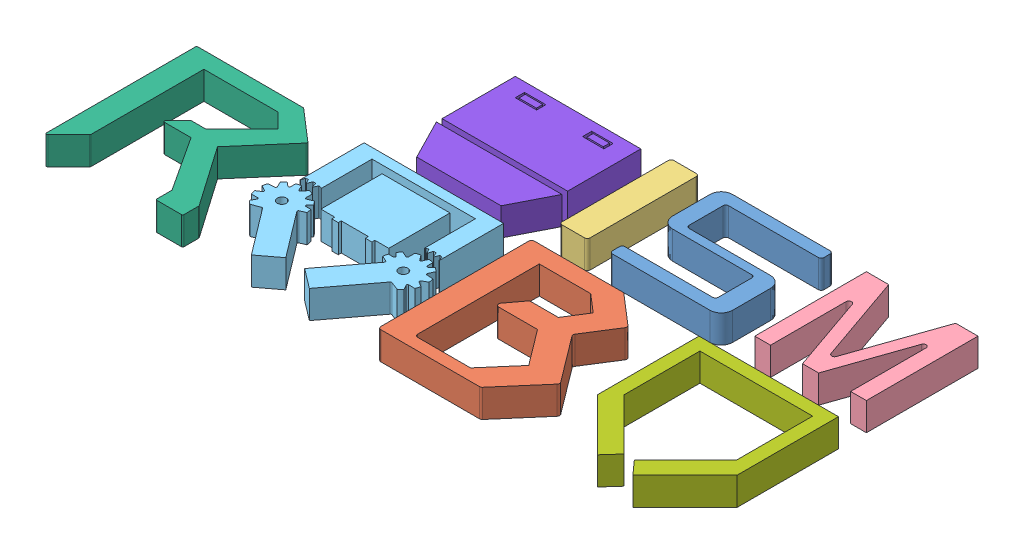
SolidWorks assembly Assem1, configuration Default. Lengths in mm.
Overall size (230 10 105).
8 component instances, 8 part files, 21 mates.
Components (placement in the parent):
- LETTER S-1: LETTER S [Default] at (-18.8633 11.7373 60.793) size (40 10 40)
- letterB-1: letterB [Default] at (-36.8633 11.7373 125.793) size (49.72 10 55)
- letterI-1: letterI [Default] at (-36.8633 11.7373 60.793) size (10 10 40)
- LetterM-1: LetterM [Default] at (33.1367 11.7373 60.793) size (40 10 40)
- letterO-1: letterO [Default] at (-96.8633 11.7373 125.793) size (59.86 10 55)
- letterR-1: letterR [Default] at (-156.8633 11.7373 125.793) size (50 10 55)
- Part5-1: Part5 [Default] at (23.1367 11.7373 125.793) size (50 10 55)
- symbol-1: symbol [Default] at (-90.391 11.7373 63.0891) size (45 10 42.7)
Mates (geometry in assembly coordinates):
- Coincident15: coincident: plane of letterO-1 through (-96.8633 21.7373 125.793) normal (0 1 0); plane of letterR-1 through (-156.8633 21.7373 135.3346) normal (0 1 0)
- Distance4: distance = 10 mm anti-aligned: plane of letterO-1 through (-46.8633 21.7373 125.793) normal (1 0 0); plane of letterB-1 through (-36.8633 21.7373 125.793) normal (-1 0 0)
- Coincident17: coincident aligned: plane of letterB-1 through (-48.8633 21.7373 125.793) normal (0 1 0); plane of letterO-1 through (-108.8633 21.7373 125.793) normal (0 1 0)
- Distance6: distance = 60 mm aligned: plane of letterB-1 through (-36.8633 21.7373 125.793) normal (-1 0 0); plane of Part5-1 through (23.1367 21.7373 107.117) normal (-1 0 0)
- Coincident21: coincident aligned: plane of letterB-1 through (-48.8633 21.7373 125.793) normal (0 1 0); plane of Part5-1 through (11.1367 21.7373 125.793) normal (0 1 0)
- Coincident22: coincident aligned: plane of letterB-1 through (-48.8633 21.7373 70.793) normal (0 0 -1); plane of Part5-1 through (11.1367 21.7373 70.793) normal (0 0 -1)
- Distance7: distance = 60 mm: plane of letterR-1 through (-156.8633 21.7373 125.793) normal (-1 0 0); plane of letterO-1 through (-96.8633 21.7373 125.793) normal (-1 0 0)
- Coincident28: coincident aligned: plane of letterO-1 through (-108.8633 21.7373 125.793) normal (0 1 0); plane of symbol-1 through (-102.391 21.7373 63.0891) normal (0 1 0)
- Distance9: distance = 5 mm anti-aligned: plane of symbol-1 through (-90.391 21.7373 65.793) normal (0 0 1); plane of letterO-1 through (-96.8633 21.7373 70.793) normal (0 0 -1)
- Coincident31: coincident anti-aligned: plane of letterO-1 through (-102.391 21.7373 125.793) normal (1 0 0); plane of symbol-1 through (-102.391 21.7373 63.0891) normal (-1 0 0)
- Coincident33: coincident aligned: plane of letterB-1 through (-48.8633 21.7373 125.793) normal (0 1 0); plane of letterI-1 through (-48.8633 21.7373 60.793) normal (0 1 0)
- Coincident37: coincident aligned: plane of letterB-1 through (-48.8633 21.7373 125.793) normal (-1 0 0); plane of letterI-1 through (-48.8633 21.7373 60.793) normal (-1 0 0)
- Coincident38: coincident aligned: plane of letterB-1 through (-48.8633 21.7373 70.793) normal (0 0 -1); plane of letterO-1 through (-108.8633 21.7373 70.793) normal (0 0 -1)
- Distance11: distance = 10 mm anti-aligned: plane of letterB-1 through (-36.8633 21.7373 70.793) normal (0 0 -1); plane of letterI-1 through (-36.8633 21.7373 60.793) normal (0 0 1)
- Coincident40: coincident aligned: plane of LETTER S-1 through (-18.8633 21.7373 60.793) normal (0 1 0); plane of letterI-1 through (-48.8633 21.7373 60.793) normal (0 1 0)
- Coincident41: coincident aligned: plane of LETTER S-1 through (-18.8633 21.7373 60.793) normal (0 0 1); plane of letterI-1 through (-48.8633 21.7373 60.793) normal (0 0 1)
- Coincident43: coincident aligned: plane of LETTER S-1 through (-18.8633 21.7373 60.793) normal (0 1 0); plane of LetterM-1 through (21.1367 21.7373 60.793) normal (0 1 0)
- Coincident44: coincident aligned: plane of LetterM-1 through (61.1367 21.7373 60.793) normal (1 0 0); plane of Part5-1 through (61.1367 21.7373 107.117) normal (1 0 0)
- Coincident45: coincident aligned: plane of LETTER S-1 through (-18.8633 21.7373 60.793) normal (0 0 1); plane of LetterM-1 through (21.1367 21.7373 60.793) normal (0 0 1)
- Distance14: distance = 8 mm anti-aligned: plane of letterI-1 through (-26.8633 21.7373 60.793) normal (1 0 0); plane of LETTER S-1 through (-18.8633 21.7373 60.793) normal (-1 0 0)
- Coincident47: coincident aligned: plane of letterO-1 through (-96.8633 21.7373 70.793) normal (0 0 -1); plane of letterR-1 through (-156.8633 21.7373 70.793) normal (0 0 -1)
